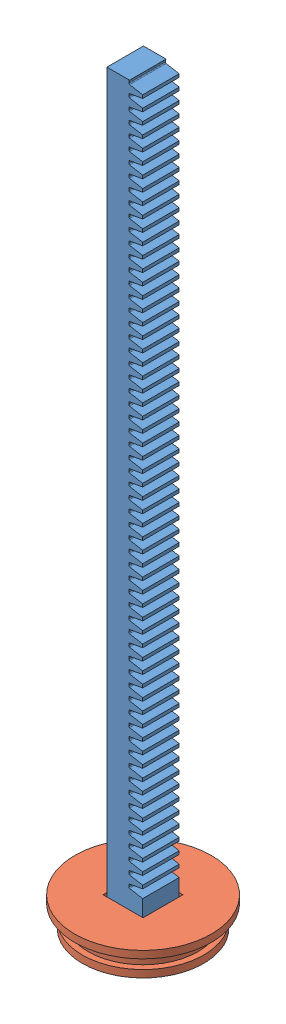
SolidWorks assembly Rack and Clip assembly, configuration Default. Lengths in mm.
Overall size (37.34 204.2 37.34).
2 component instances, 2 part files, 1 mates.
Components (placement in the parent):
- Rack FLAT Small Syringe .35tip .20tillflat .50edge-1: Rack FLAT Small Syringe .35tip .20tillflat .50edge [100mm length] at (42.6296 273.0469 165.1791) x (0 1 0) z (0 0 -1) size (203.2 12.7 10)
- clip5-1: clip5 [Default] at (47.5296 19.8869 165.1791) x (-1 0 0) z (0 0 1) size (37.34 8 37.34)
Mates (geometry in assembly coordinates):
- ProfileCenter1: profile center anti-aligned: plane of Rack FLAT Small Syringe .35tip .20tillflat .50edge-1 through (42.6296 12.8869 183.8574) normal (0 -1 0); plane of clip5-1 through (47.5296 12.8869 165.1791) normal (0 1 0)
